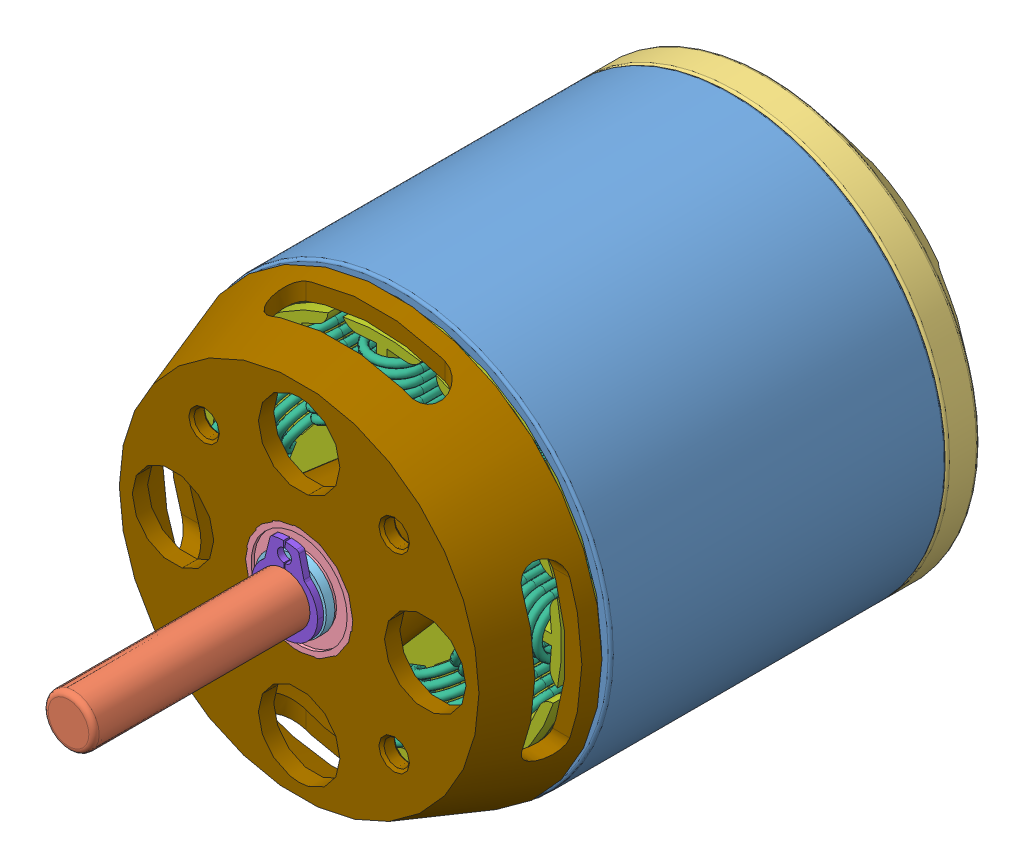
SolidWorks assembly BLDC Motor Turnigy Aerodrive SK3 350KV Outrunner, configuration Default. Lengths in mm.
Overall size (41.68 41.68 79.44).
35 component instances, 14 part files, 0 mates.
Components (placement in the parent):
- BLDC Motor Turnigy Aerodrive SK3 350KV Outrunner.stp-1: BLDC Motor Turnigy Aerodrive SK3 350KV Outrunner.stp [Default] at origin size (44.72 127.44 79.44)
  - SK3 350KV Lower Outer Shell_MODEL.stp-1: SK3 350KV Lower Outer Shell_MODEL.stp [Default] at (0 0 -56.866) size (41.68 41.68 79.44)
    - Lower_Can.stp-1: Lower_Can.stp [Default] at (0 0 14.2875) size (41.63 41.63 32.89)
    - Shaft.stp-1: Shaft.stp [Default] at origin size (5 5 79.44)
    - Lower_Cap.stp-1: Lower_Cap.stp [Default] at origin size (41.68 41.68 16.07)
  - SK3 350KV Upper Assembly_MODEL.stp-1: SK3 350KV Upper Assembly_MODEL.stp [Default] at (0 0 -10.2) size (44.58 124 45.83)
    - Power Cables.stp-1: Power Cables.stp [Default] at origin size (27.21 94.31 9.98) (hidden)
    - 6mm Bearing.stp-1: 6mm Bearing.stp [Default] at (0 0 7.2) size (10.5 10.5 3)
    - 5 to 6 mm bushing.stp-1: 5 to 6 mm bushing.stp [Default] at (0 0 11.0382) size (7 7 3.33)
    - Stator_Coils.stp-1: Stator_Coils.stp [Default] at (0 -9.652 0.7009) size (5.33 7.16 33.27)
    - Stator_Steel_Laminations.stp-1: Stator_Steel_Laminations.stp [Default] at (0 0 -28.257) size (35.18 35.18 30.35)
    - 98541A113_BLACK-FINISH STEEL EXTERNAL RETAINING RING_step.stp-1: 98541A113_BLACK-FINISH STEEL EXTERNAL RETAINING RING_step.stp [Default] at (0 0 11.3382) x (0 0 -1) z (1 0 0) size (0.6 8.3 6.49)
    - Stator_Coils.stp-2: Stator_Coils.stp [Default] at (4.826 -8.3589 0.7009) x (0.866025 0.5 0) z (0 0 1) size (5.33 7.16 33.27)
    - Stator_Coils.stp-3: Stator_Coils.stp [Default] at (8.3589 -4.826 0.7009) x (0.5 0.866025 0) z (0 0 1) size (5.33 7.16 33.27)
    - Stator_Coils.stp-4: Stator_Coils.stp [Default] at (9.652 0 0.7009) x (0 1 0) z (0 0 1) size (5.33 7.16 33.27)
    - Stator_Coils.stp-5: Stator_Coils.stp [Default] at (8.3589 4.826 0.7009) x (-0.5 0.866025 0) z (0 0 1) size (5.33 7.16 33.27)
    - Stator_Coils.stp-6: Stator_Coils.stp [Default] at (4.826 8.3589 0.7009) x (-0.866025 0.5 0) z (0 0 1) size (5.33 7.16 33.27)
    - Stator_Coils.stp-7: Stator_Coils.stp [Default] at (0 9.652 0.7009) x (-1 0 0) z (0 0 1) size (5.33 7.16 33.27)
    - Stator_Coils.stp-8: Stator_Coils.stp [Default] at (-4.826 8.3589 0.7009) x (-0.866025 -0.5 0) z (0 0 1) size (5.33 7.16 33.27)
    - Stator_Coils.stp-9: Stator_Coils.stp [Default] at (-8.3589 4.826 0.7009) x (-0.5 -0.866025 0) z (0 0 1) size (5.33 7.16 33.27)
    - Stator_Coils.stp-10: Stator_Coils.stp [Default] at (-9.652 0 0.7009) x (0 -1 0) z (0 0 1) size (5.33 7.16 33.27)
    - Stator_Coils.stp-11: Stator_Coils.stp [Default] at (-8.3589 -4.826 0.7009) x (0.5 -0.866025 0) z (0 0 1) size (5.33 7.16 33.27)
    - Stator_Coils.stp-12: Stator_Coils.stp [Default] at (-4.826 -8.3589 0.7009) x (0.866025 -0.5 0) z (0 0 1) size (5.33 7.16 33.27)
    - 91290A111_BLACK-OXIDE CLASS 12.9 SOCKET HEAD CAP SCREW_step.stp-1: 91290A111_BLACK-OXIDE CLASS 12.9 SOCKET HEAD CAP SCREW_step.stp [Default] at (-9.302 9.302 6.922) x (-1 0 0) z (0 0 -1) size (5.5 5.5 9) (hidden)
    - 91290A111_BLACK-OXIDE CLASS 12.9 SOCKET HEAD CAP SCREW_step.stp-2: 91290A111_BLACK-OXIDE CLASS 12.9 SOCKET HEAD CAP SCREW_step.stp [Default] at (-9.302 -9.302 6.922) x (-1 0 0) z (0 0 -1) size (5.5 5.5 9) (hidden)
    - 91290A111_BLACK-OXIDE CLASS 12.9 SOCKET HEAD CAP SCREW_step.stp-3: 91290A111_BLACK-OXIDE CLASS 12.9 SOCKET HEAD CAP SCREW_step.stp [Default] at (9.302 -9.302 6.922) x (-1 0 0) z (0 0 -1) size (5.5 5.5 9) (hidden)
    - 91290A111_BLACK-OXIDE CLASS 12.9 SOCKET HEAD CAP SCREW_step.stp-4: 91290A111_BLACK-OXIDE CLASS 12.9 SOCKET HEAD CAP SCREW_step.stp [Default] at (9.302 9.302 6.922) x (-1 0 0) z (0 0 -1) size (5.5 5.5 9) (hidden)
    - SK3 350KV Upper Assembly_MODEL-0.stp-1: SK3 350KV Upper Assembly_MODEL-0.stp [Default] at origin size (41.4 41.4 9.43)
  - Motor_Mount_Bracket_MODEL.stp-1: Motor_Mount_Bracket_MODEL.stp [Default] at (0 0 0.0762) x (0 -1 0) z (0 0 1) size (48.27 27.49 15.17)
    - 91290A101_BLACK-OXIDE CLASS 12.9 SOCKET HEAD CAP SCREW_step.stp-1: 91290A101_BLACK-OXIDE CLASS 12.9 SOCKET HEAD CAP SCREW_step.stp [Default] at (-21.59 -7.2912 15.1681) x (-1 0 0) z (0 0 1) size (4.5 4.5 8.5) (hidden)
    - 91290A101_BLACK-OXIDE CLASS 12.9 SOCKET HEAD CAP SCREW_step.stp-2: 91290A101_BLACK-OXIDE CLASS 12.9 SOCKET HEAD CAP SCREW_step.stp [Default] at (-21.59 7.9488 15.1681) x (-1 0 0) z (0 0 1) size (4.5 4.5 8.5) (hidden)
    - 91290A101_BLACK-OXIDE CLASS 12.9 SOCKET HEAD CAP SCREW_step.stp-3: 91290A101_BLACK-OXIDE CLASS 12.9 SOCKET HEAD CAP SCREW_step.stp [Default] at (21.59 7.9488 15.1681) x (-1 0 0) z (0 0 1) size (4.5 4.5 8.5) (hidden)
    - 91290A101_BLACK-OXIDE CLASS 12.9 SOCKET HEAD CAP SCREW_step.stp-4: 91290A101_BLACK-OXIDE CLASS 12.9 SOCKET HEAD CAP SCREW_step.stp [Default] at (21.59 -7.2912 15.1681) x (-1 0 0) z (0 0 1) size (4.5 4.5 8.5) (hidden)
    - Motor_Mount_Bracket_MODEL-1.stp-1: Motor_Mount_Bracket_MODEL-1.stp [Default] at origin size (48.27 27.49 11.68) (hidden)
  - PInion_gear.stp-1: PInion_gear.stp [Default] at (0 0 11.9045) x (-1 0 0) z (0 0 -1) size (36.98 36.98 10.16) (hidden)
